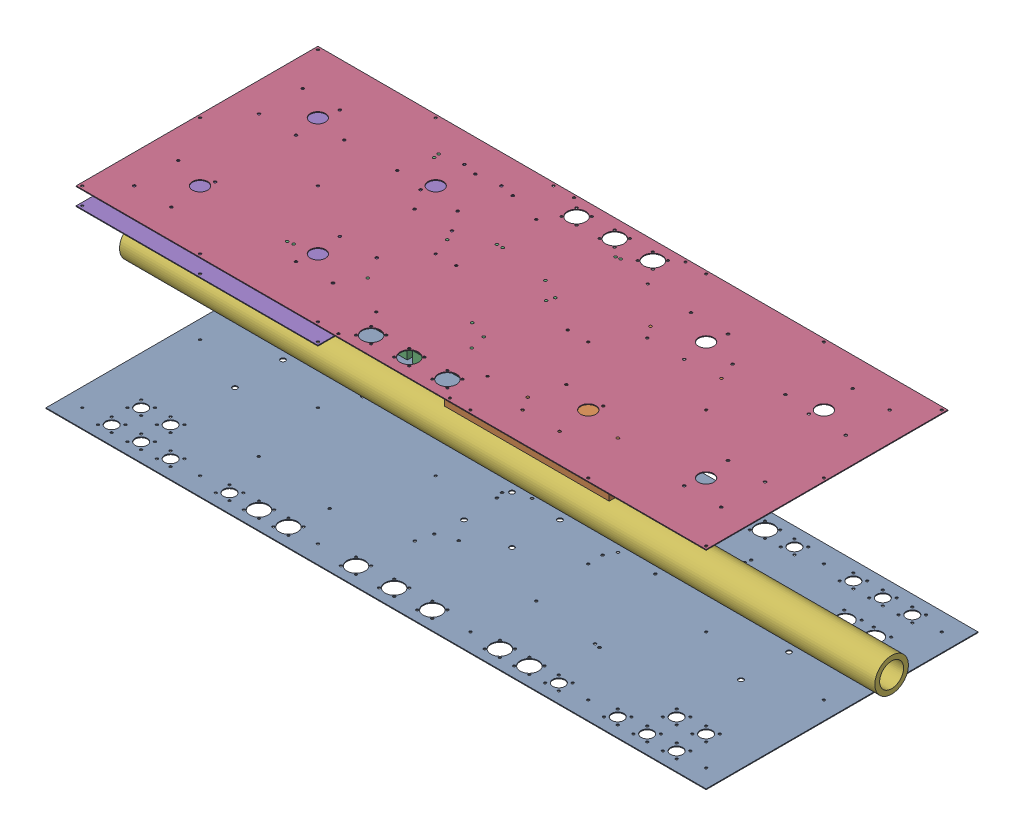
SolidWorks assembly antenna_box, configuration Default. Lengths in mm.
Overall size (1000 255.53 360).
6 component instances, 6 part files, 8 mates.
Components (placement in the parent):
- panel1-1: panel1 [Default] at origin size (874 1.02 360)
- eval-adrv9026-1: eval-adrv9026 [Default] at (-167.4337 215.53 90.7906) x (1 0 0) z (0 0 -1) size (236.73 50 193.04)
- ads9-v2ebz-1: ads9-v2ebz [Default] at (106.5266 225.53 -17.0085) x (1 0 0) z (0 0 -1) size (259.71 65 215.9)
- panel2-1: panel2 [Default] at (0 255.53 0) x (1 0 0) z (0 0 -1) size (834 1.02 320)
- subpanel-1: subpanel [Default] at (-257 231.5991 0) size (320 1.02 320) (hidden)
- big_pipe-1: big_pipe [Default] at (0.019 71.9832 -2.6192) x (0 -1 0) z (0 0 1) size (44.45 1000 44.45)
Mates (geometry in assembly coordinates):
- Concentric1: concentric anti-aligned: circle of panel1-1; circle of panel2-1
- Parallel1: parallel aligned: plane of panel1-1 through (-437 1.016 -180) normal (-1 0 0); plane of big_pipe-1 through (-499.981 71.9832 -2.6192) normal (-1 0 0)
- Parallel2: parallel aligned: line of ads9-v2ebz-1 through (39.6644 220.53 91.182) axis (-1 0 0); line of panel2-1 through (417 254.514 160) axis (-1 0 0)
- Parallel3: parallel aligned: line of eval-adrv9026-1 through (247.4888 205.53 118.8143) axis (-1 0 0); line of panel2-1 through (417 254.514 160) axis (-1 0 0)
- Parallel4: parallel anti-aligned: line of panel1-1 through (-437 0 180) axis (1 0 0); line of panel2-1 through (417 254.514 160) axis (-1 0 0)
- Concentric2: concentric anti-aligned: circle of panel1-1; circle of panel2-1
- Coincident1: coincident anti-aligned: circle of eval-adrv9026-1; circle of panel2-1
- Coincident2: coincident aligned: circle of ads9-v2ebz-1; circle of panel2-1
